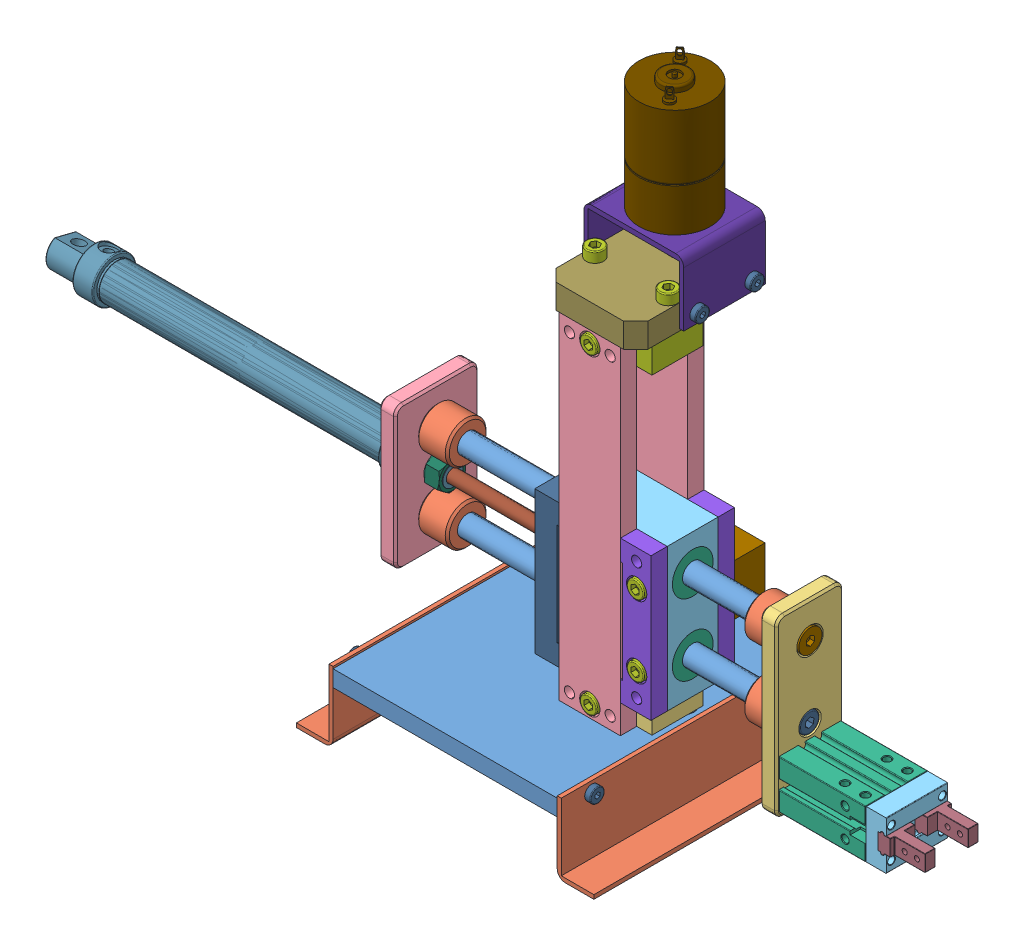
SolidWorks assembly handling, configuration Default. Lengths in mm.
Overall size (436.7 290 125).
70 component instances, 33 part files, 172 mates.
Components (placement in the parent):
- tam de lon-1: tam de lon [Default] at (42.5889 56.6685 101.1963) size (110 8 125)
- khoi do-1: khoi do [Default] at (98.4472 49.4552 163.6963) x (0 0 -1) z (-1 0 0) size (125 35 18)
- khoi do-2: khoi do [Default] at (-13.2695 49.4552 38.6963) x (0 0 1) z (1 0 0) size (125 35 18)
- mieng dem duoi-1: mieng dem duoi [Default] at (71.5889 64.6685 101.1963) size (45 12 25)
- thanh dan huong lon x2-1: thanh dan huong lon x2 [Default] at (71.5889 147.1685 113.6963) x (1 0 0) z (0 -1 0) size (30 8 165)
- thanh dan huong lon x2-2: thanh dan huong lon x2 [Default] at (71.5889 147.1685 88.6963) x (1 0 0) z (0 1 0) size (30 8 165)
- con truot s4 -1: con truot s4  [Default] at (79.0889 78.6685 101.1963) x (-1 0 0) z (0 0 -1) size (45 70 25)
- bac lot-1: bac lot [Default] at (101.5889 96.1685 101.1963) x (0 1 0) z (0 0 1) size (20 12 20)
- bac lot-2: bac lot [Default] at (101.5889 131.1685 101.1963) x (0 1 0) z (0 0 1) size (20 12 20)
- bac lot-3: bac lot [Default] at (56.5889 131.1685 101.1963) x (0 0.381849 -0.924225) z (0 -0.924225 -0.381849) size (20 12 20)
- bac lot-4: bac lot [Default] at (56.5889 96.1685 101.1963) x (0 0.381849 -0.924225) z (0 -0.924225 -0.381849) size (20 12 20)
- mieng dem tren-1: mieng dem tren [Default] at (71.5889 217.6685 101.1963) size (45 12 25)
- thanh dan huong so 2 s4-3: thanh dan huong so 2 s4 [Default] at (94.0889 113.6685 88.6963) x (-1 0 0) z (0 -1 0) size (15 8 70)
- thanh ngang-5: thanh ngang [Default] at (73.0889 110.6685 65.6963) x (-1 0 0) z (0 1 0) size (57 15 25)
- tam dan huong-4: tam dan huong [Default] at (44.5889 113.6685 101.1963) x (0 -1 0) z (0 0 1) size (70 12 41)
- dai oc-1: dai oc [Default] at (71.5889 113.6685 65.6963) x (0 1 0) z (1 0 0) size (16 14 16)
- tam de nho-4: tam de nho [Default] at (71.5889 241.6685 90.6963) x (1 0 0) z (0 0 -1) size (45 12 62)
- dau kep truc vit-2: dau kep truc vit [Default] at (71.5889 256.8685 72.6963) x (-0.681909 0 -0.731437) z (-0.731437 0 0.681909) size (20 25 20)
- vong_dem-2: vong_dem [Default] at (71.5889 229.8685 72.6963) x (0.969315 0 0.245821) z (-0.245821 0 0.969315) size (19.6 2 19.6)
- vit me M8x150mm-2: vit me M8x150mm [Default] at (71.5889 171.8685 72.6963) x (0.994213 0 -0.107422) z (0 1 0) size (10.85 10.06 150.11)
- hex nut gradec_din-2: hex nut gradec_din [Hexagon Nut ISO 4034 - M8 - N] at (71.5889 221.9685 72.6963) x (-0.968146 0 0.250385) z (0 -1 0) size (13 15.01 7.9)
- de dong co-1: de dong co [Default] at (71.6847 246.1685 60.1963) x (1 0 0) z (0 -1 0) size (49 40 31)
- moto-1: moto [Default] at (71.7593 263.8856 80.1944) x (0 -1 0) z (0.022721 0 0.999742) size (78 35 35)
- chot dan huong-1: chot dan huong [Default] at (151.1424 131.1685 101.1963) x (0 0.988897 -0.148604) z (0 0.148604 0.988897) size (10 175 10)
- chot dan huong-2: chot dan huong [Default] at (151.1424 96.1685 101.1963) x (0 0.324021 0.94605) z (0 -0.94605 0.324021) size (10 175 10)
- bac chan-1: bac chan [Default] at (151.1424 131.1685 101.1963) x (0 -0.987145 -0.159829) z (0 0.159829 -0.987145) size (20 15 20)
- bac chan-2: bac chan [Default] at (151.1424 96.1685 101.1963) x (0 1 0) z (0 0 1) size (20 15 20)
- bac chan-3: bac chan [Default] at (-8.8576 131.1685 101.1963) x (0 -0.034971 0.999388) z (0 -0.999388 -0.034971) size (20 15 20)
- bac chan-4: bac chan [Default] at (-8.8576 96.1685 101.1963) x (0 0.99939 -0.03491) z (0 0.03491 0.99939) size (20 15 20)
- ban canh truoc-1: ban canh truoc [Default] at (151.1424 105.6685 101.1963) x (0 0 -1) z (0 -1 0) size (33 8 86)
- ban canh sau-1: ban canh sau [Default] at (-23.8576 113.6685 101.1963) x (0 0 -1) z (0 1 0) size (41 8 70)
- NMHZ2-16D-2: NMHZ2-16D [Default] at (144.1545 75.1106 123.6032) x (0 0 -1) z (1 0 0) size (30.6 23.6 52.5)
  - NMHZ2-16D Slipway-1: NMHZ2-16D Slipway [Default] at (22.4069 2.6078 57.488) size (30.1 23.6 10)
  - NMHZ2-16D cylinder-2: NMHZ2-16D cylinder [Default] at (22.4069 2.6078 14.988) size (30.6 23.6 42.5)
- socket head cap screw_din-2: socket head cap screw_din [DIN 912 M5 x 16 --- 16N] at (94.5889 131.1685 79.8963) x (0 0 1) z (-1 0 0) size (21 8.5 8.5)
- socket head cap screw_din-3: socket head cap screw_din [DIN 912 M5 x 16 --- 16N] at (50.0889 107.1685 66.3963) x (0 0 1) z (-1 0 0) size (21 8.5 8.5)
- socket head cap screw_din-4: socket head cap screw_din [DIN 912 M5 x 16 --- 16N] at (94.5889 120.1685 66.3963) x (0 0 1) z (-1 0 0) size (21 8.5 8.5)
- socket head cap screw_din-5: socket head cap screw_din [DIN 912 M5 x 16 --- 16N] at (94.5889 96.1685 79.8963) x (0 0 1) z (-1 0 0) size (21 8.5 8.5)
- socket head cap screw_din-6: socket head cap screw_din [DIN 912 M5 x 16 --- 16N] at (71.5889 70.6685 79.8963) x (0 0 1) z (-1 0 0) size (21 8.5 8.5)
- socket head cap screw_din-9: socket head cap screw_din [DIN 912 M5 x 8 --- 8N] at (71.5889 70.6685 122.4963) x (0 0 -1) z (1 0 0) size (13 8.5 8.5)
- socket head cap screw_din-10: socket head cap screw_din [DIN 912 M5 x 8 --- 8N] at (45.2889 84.6685 108.6963) size (13 8.5 8.5)
- socket head cap screw_din-11: socket head cap screw_din [DIN 912 M5 x 8 --- 8N] at (45.2889 142.6685 93.6963) size (13 8.5 8.5)
- thanh dan huong s4-1: thanh dan huong s4 [Default] at (94.0889 113.6685 113.6963) x (-1 0 0) z (0 1 0) size (15 8 70)
- socket head cap screw_din-13: socket head cap screw_din [DIN 912 M5 x 12 --- 12N] at (94.5889 96.1685 122.4963) x (0 0 -1) z (1 0 0) size (17 8.5 8.5)
- socket head cap screw_din-14: socket head cap screw_din [DIN 912 M5 x 12 --- 12N] at (94.5889 131.1685 122.4963) x (0 0 -1) z (1 0 0) size (17 8.5 8.5)
- socket head cap screw_din-15: socket head cap screw_din [DIN 912 M5 x 12 --- 12N] at (53.5889 246.6685 101.1963) x (0 -1 0) z (0 0 1) size (17 8.5 8.5)
- socket head cap screw_din-16: socket head cap screw_din [DIN 912 M5 x 12 --- 12N] at (89.5889 246.6685 101.1963) x (0 -1 0) z (0 0 1) size (17 8.5 8.5)
- socket head cap screw_din-17: socket head cap screw_din [DIN 912 M5 x 12 --- 12N] at (71.5889 223.6685 79.8963) x (0 0 1) z (-1 0 0) size (17 8.5 8.5)
- socket head cap screw_din-18: socket head cap screw_din [DIN 912 M5 x 12 --- 12N] at (71.5889 223.6685 122.4963) x (0 0 -1) z (1 0 0) size (17 8.5 8.5)
- socket csink head cap screw 10642_din-2: socket csink head cap screw 10642_din [EN ISO 10642 - M6 x 8 - 8N] at (-32.0776 131.1685 101.1963) x (1 0 0) z (0 0.02259 0.999745) size (8 11.34 11.34)
- socket csink head cap screw 10642_din-3: socket csink head cap screw 10642_din [EN ISO 10642 - M6 x 8 - 8N] at (159.3624 131.1685 101.1963) x (-1 0 0) z (0 -0.022602 -0.999745) size (8 11.34 11.34)
- socket head thin cap screw_din-2: socket head thin cap screw_din [DIN 7984 - M6 x 10 --- 7N] at (158.9424 96.1685 101.1963) x (-1 0 0) z (0 0.924225 0.381849) size (14 10 10)
- socket head thin cap screw_din-4: socket head thin cap screw_din [DIN 7984 - M6 x 10 --- 7N] at (-31.6576 96.1685 101.1963) size (14 10 10)
- socket head thin cap screw_din-5: socket head thin cap screw_din [DIN 7984 - M4 x 6 --- 3.9N] at (-17.2111 60.6685 53.6963) size (8.8 7 7)
- socket head thin cap screw_din-6: socket head thin cap screw_din [DIN 7984 - M4 x 6 --- 3.9N] at (-17.2111 60.6685 148.6963) size (8.8 7 7)
- socket head thin cap screw_din-7: socket head thin cap screw_din [DIN 7984 - M4 x 6 --- 3.9N] at (102.3889 60.6685 53.6963) x (-1 0 0) z (0 0.924225 0.381849) size (8.8 7 7)
- socket head thin cap screw_din-8: socket head thin cap screw_din [DIN 7984 - M4 x 6 --- 3.9N] at (102.3889 60.6685 148.6963) x (-1 0 0) z (0 0.924225 0.381849) size (8.8 7 7)
- socket head thin cap screw_din-10: socket head thin cap screw_din [DIN 7984 - M4 x 12 --- 9.9N] at (152.7424 70.3685 112.1963) size (14.8 7 7)
- socket head thin cap screw_din-11: socket head thin cap screw_din [DIN 7984 - M4 x 12 --- 9.9N] at (152.7424 85.3685 90.1963) size (14.8 7 7)
- socket head thin cap screw_din-13: socket head thin cap screw_din [DIN 7984 - M4 x 6 --- 3.9N] at (98.9847 235.6685 66.6963) x (-1 0 0) z (0 0.924225 0.381849) size (8.8 7 7)
- socket head thin cap screw_din-14: socket head thin cap screw_din [DIN 7984 - M4 x 6 --- 3.9N] at (98.9847 235.6685 93.6963) x (-1 0 0) z (0 0.924225 0.381849) size (8.8 7 7)
- socket head thin cap screw_din-15: socket head thin cap screw_din [DIN 7984 - M4 x 6 --- 3.9N] at (44.3847 235.6685 66.6963) size (8.8 7 7)
- socket head thin cap screw_din-16: socket head thin cap screw_din [DIN 7984 - M4 x 6 --- 3.9N] at (44.3847 235.6685 93.6963) size (8.8 7 7)
- socket head thin cap screw_din-18: socket head thin cap screw_din [DIN 7984 - M3 x 5 --- 3.5N] at (67.1565 252.8685 67.942) x (0.681909 0 0.731437) z (0.731403 -0.009583 -0.681878) size (7 5.5 5.5)
- Rod-1: Rod [Default] at (-92.4392 113.6685 101.1963) x (0 0.994852 -0.101337) z (0 -0.101337 -0.994852) size (6.2 165 6.2)
- Nut 5-1: Nut 5 [Default] at (55.0889 113.6685 101.1963) x (0 -0.278581 0.960413) z (0 0.960413 0.278581) size (11.32 3 9.8)
- NMHZ2-16D air claw-1: NMHZ2-16D air claw [Default] at (209.6424 77.7185 98.1463) x (0 0 -1) z (1 0 0) size (12 10 21)
- NMHZ2-16D air claw-2: NMHZ2-16D air claw [Default] at (209.6424 77.7185 104.2463) x (0 0 1) z (1 0 0) size (12 10 21)
- 16 X 100 Cylinder bore-3: 16 X 100 Cylinder bore [Default] at (-112.0576 113.6685 101.1963) x (0 0.970405 -0.241483) z (-1 0 0) size (21.5 21.5 192)
- hex nut style 2 fine gradeab_din-4: hex nut style 2 fine gradeab_din [Hexagon Nut ISO 8674 - M8 x 1 - W - N] at (-16.3576 113.6685 101.1963) x (0 0.810685 -0.585482) z (1 0 0) size (13 15.01 7.5)
Mates (geometry in assembly coordinates):
- Parallel1: parallel anti-aligned: plane of tam de lon-1 through (42.5889 64.6685 101.1963) normal (0 1 0); plane of khoi do-1 through (97.5889 30.6685 38.6963) normal (0 -1 0)
- Parallel2: parallel anti-aligned: plane of tam de lon-1 through (97.5889 64.6685 38.6963) normal (1 0 0); plane of khoi do-1 through (97.5889 30.6685 38.6963) normal (-1 0 0)
- Concentric1: concentric aligned: cylinder of tam de lon-1 through (82.5889 60.6685 53.6963) axis (1 0 0) radius 2.5; cylinder of khoi do-1 through (-25.4111 60.6685 53.6963) axis (1 0 0) radius 2.5
- Coincident1: coincident anti-aligned: plane of tam de lon-1 through (97.5889 64.6685 38.6963) normal (1 0 0); plane of khoi do-1 through (97.5889 30.6685 38.6963) normal (-1 0 0)
- Parallel3: parallel anti-aligned: plane of tam de lon-1 through (42.5889 64.6685 101.1963) normal (0 1 0); plane of khoi do-2 through (-12.4111 30.6685 163.6963) normal (0 -1 0)
- Parallel4: parallel anti-aligned: plane of tam de lon-1 through (-12.4111 64.6685 38.6963) normal (-1 0 0); plane of khoi do-2 through (-12.4111 30.6685 163.6963) normal (1 0 0)
- Concentric2: concentric aligned: cylinder of tam de lon-1 through (2.5889 60.6685 148.6963) axis (-1 0 0) radius 2.5; cylinder of khoi do-2 through (110.5889 60.6685 148.6963) axis (-1 0 0) radius 2.5
- Coincident2: coincident anti-aligned: plane of tam de lon-1 through (-12.4111 64.6685 38.6963) normal (-1 0 0); plane of khoi do-2 through (-12.4111 30.6685 163.6963) normal (1 0 0)
- Concentric3: concentric aligned: cylinder of tam de lon-1 through (89.5889 56.6685 93.6963) axis (0 1 0) radius 2.75; cylinder of mieng dem duoi-1 through (89.5889 64.6685 93.6963) axis (0 1 0) radius 2.5
- Concentric4: concentric aligned: cylinder of tam de lon-1 through (53.5889 56.6685 108.6963) axis (0 1 0) radius 2.75; cylinder of mieng dem duoi-1 through (53.5889 64.6685 108.6963) axis (0 1 0) radius 2.5
- Coincident3: coincident anti-aligned: plane of tam de lon-1 through (42.5889 64.6685 101.1963) normal (0 1 0); plane of mieng dem duoi-1 through (71.5889 64.6685 101.1963) normal (0 -1 0)
- Parallel6: parallel anti-aligned: plane of mieng dem duoi-1 through (71.5889 76.6685 101.1963) normal (0 1 0); plane of thanh dan huong lon x2-1 through (56.5889 64.6685 121.6963) normal (0 -1 0)
- Parallel7: parallel anti-aligned: plane of mieng dem duoi-1 through (49.0889 76.6685 113.6963) normal (0 0 1); plane of thanh dan huong lon x2-1 through (71.5889 147.1685 113.6963) normal (0 0 -1)
- Concentric5: concentric anti-aligned: cylinder of mieng dem duoi-1 through (81.5889 70.6685 160.6963) axis (0 0 -1) radius 2.5; cylinder of thanh dan huong lon x2-1 through (81.5889 70.6685 80.4963) axis (0 0 1) radius 2.5
- Coincident4: coincident anti-aligned: plane of mieng dem duoi-1 through (49.0889 76.6685 113.6963) normal (0 0 1); plane of thanh dan huong lon x2-1 through (71.5889 147.1685 113.6963) normal (0 0 -1)
- Parallel8: parallel anti-aligned: plane of mieng dem duoi-1 through (71.5889 76.6685 101.1963) normal (0 1 0); plane of thanh dan huong lon x2-2 through (56.5889 64.6685 80.6963) normal (0 -1 0)
- Parallel9: parallel anti-aligned: plane of mieng dem duoi-1 through (49.0889 76.6685 88.6963) normal (0 0 -1); plane of thanh dan huong lon x2-2 through (71.5889 147.1685 88.6963) normal (0 0 1)
- Concentric6: concentric aligned: cylinder of mieng dem duoi-1 through (81.5889 70.6685 160.6963) axis (0 0 -1) radius 2.5; cylinder of thanh dan huong lon x2-2 through (81.5889 70.6685 121.8963) axis (0 0 -1) radius 2.5
- Coincident5: coincident anti-aligned: plane of mieng dem duoi-1 through (49.0889 76.6685 88.6963) normal (0 0 -1); plane of thanh dan huong lon x2-2 through (71.5889 147.1685 88.6963) normal (0 0 1)
- Parallel10: parallel anti-aligned: plane of mieng dem duoi-1 through (94.0889 76.6685 88.6963) normal (1 0 0); plane of con truot s4 -1 through (56.5889 148.6685 113.6963) normal (-1 0 0)
- Parallel11: parallel aligned: plane of mieng dem duoi-1 through (71.5889 76.6685 101.1963) normal (0 1 0); plane of con truot s4 -1 through (79.0889 148.6685 101.1963) normal (0 1 0)
- Coincident6: coincident anti-aligned: plane of thanh dan huong lon x2-2 through (71.5889 147.1685 88.6963) normal (0 0 1); plane of con truot s4 -1 through (101.5889 148.6685 88.6963) normal (0 0 -1)
- Concentric7: concentric anti-aligned: cylinder of con truot s4 -1 through (126.5889 96.1685 101.1963) axis (-1 0 0) radius 6; cylinder of bac lot-1 through (89.5889 96.1685 101.1963) axis (1 0 0) radius 6
- Coincident14: coincident anti-aligned: plane of con truot s4 -1 through (99.5889 96.1685 101.1963) normal (1 0 0); plane of bac lot-1 through (99.5889 96.1685 101.1963) normal (-1 0 0)
- Concentric8: concentric anti-aligned: cylinder of con truot s4 -1 through (126.5889 131.1685 101.1963) axis (-1 0 0) radius 6; cylinder of bac lot-2 through (89.5889 131.1685 101.1963) axis (1 0 0) radius 6
- Coincident15: coincident anti-aligned: plane of con truot s4 -1 through (99.5889 131.1685 101.1963) normal (1 0 0); plane of bac lot-2 through (99.5889 131.1685 101.1963) normal (-1 0 0)
- Concentric9: concentric aligned: cylinder of con truot s4 -1 through (126.5889 131.1685 101.1963) axis (-1 0 0) radius 6; cylinder of bac lot-3 through (68.5889 131.1685 101.1963) axis (-1 0 0) radius 6
- Coincident16: coincident anti-aligned: plane of con truot s4 -1 through (58.5889 131.1685 101.1963) normal (-1 0 0); plane of bac lot-3 through (58.5889 131.1685 101.1963) normal (1 0 0)
- Concentric10: concentric aligned: cylinder of con truot s4 -1 through (126.5889 96.1685 101.1963) axis (-1 0 0) radius 6; cylinder of bac lot-4 through (68.5889 96.1685 101.1963) axis (-1 0 0) radius 6
- Coincident18: coincident anti-aligned: plane of con truot s4 -1 through (58.5889 96.1685 101.1963) normal (-1 0 0); plane of bac lot-4 through (58.5889 96.1685 101.1963) normal (1 0 0)
- Parallel23: parallel aligned: plane of thanh dan huong lon x2-2 through (56.5889 229.6685 80.6963) normal (0 1 0); plane of mieng dem tren-1 through (71.5889 229.6685 101.1963) normal (0 1 0)
- Concentric12: concentric aligned: cylinder of thanh dan huong lon x2-2 through (61.5889 223.6685 121.8963) axis (0 0 -1) radius 2.5; cylinder of mieng dem tren-1 through (61.5889 223.6685 160.6963) axis (0 0 -1) radius 2.5
- Coincident21: coincident anti-aligned: plane of thanh dan huong lon x2-2 through (71.5889 147.1685 88.6963) normal (0 0 1); plane of mieng dem tren-1 through (49.0889 229.6685 88.6963) normal (0 0 -1)
- Parallel38: parallel aligned: plane of con truot s4 -1 through (79.0889 148.6685 101.1963) normal (0 1 0); plane of thanh dan huong so 2 s4-3 through (101.5889 148.6685 80.6963) normal (0 1 0)
- Parallel39: parallel anti-aligned: plane of con truot s4 -1 through (101.5889 148.6685 88.6963) normal (0 0 -1); plane of thanh dan huong so 2 s4-3 through (94.0889 113.6685 88.6963) normal (0 0 1)
- Coincident32: coincident aligned: plane of con truot s4 -1 through (79.0889 148.6685 101.1963) normal (0 1 0); plane of thanh dan huong so 2 s4-3 through (101.5889 148.6685 80.6963) normal (0 1 0)
- Coincident33: coincident aligned: plane of con truot s4 -1 through (101.5889 148.6685 113.6963) normal (1 0 0); plane of thanh dan huong so 2 s4-3 through (101.5889 148.6685 80.6963) normal (1 0 0)
- Coincident34: coincident anti-aligned: plane of con truot s4 -1 through (101.5889 148.6685 88.6963) normal (0 0 -1); plane of thanh dan huong so 2 s4-3 through (94.0889 113.6685 88.6963) normal (0 0 1)
- Coincident36: coincident anti-aligned: plane of thanh dan huong lon x2-2 through (86.5889 64.6685 80.6963) normal (1 0 0); plane of thanh dan huong so 2 s4-3 through (86.5889 148.6685 80.6963) normal (-1 0 0)
- Parallel42: parallel anti-aligned: plane of thanh dan huong so 2 s4-3 through (101.5889 148.6685 80.6963) normal (0 1 0); plane of thanh ngang-5 through (101.5889 101.1685 80.6963) normal (0 -1 0)
- Concentric26: concentric aligned: cylinder of thanh dan huong so 2 s4-3 through (94.5889 120.1685 152.8963) axis (0 0 -1) radius 2.5; cylinder of thanh ngang-5 through (94.5889 120.1685 124.3963) axis (0 0 -1) radius 2.75
- Parallel46: parallel aligned: plane of con truot s4 -1 through (79.0889 148.6685 101.1963) normal (0 1 0); plane of tam dan huong-4 through (56.5889 148.6685 80.6963) normal (0 1 0)
- Parallel47: parallel anti-aligned: plane of con truot s4 -1 through (56.5889 148.6685 113.6963) normal (-1 0 0); plane of tam dan huong-4 through (55.5889 138.6685 33.6963) normal (1 0 0)
- Coincident40: coincident anti-aligned: plane of con truot s4 -1 through (56.5889 148.6685 113.6963) normal (-1 0 0); plane of tam dan huong-4 through (56.5889 113.6685 101.1963) normal (1 0 0)
- Concentric29: concentric aligned: cylinder of con truot s4 -1 through (71.5889 142.6685 93.6963) axis (-1 0 0) radius 2.5; cylinder of tam dan huong-4 through (132.5889 142.6685 93.6963) axis (-1 0 0) radius 2.75
- Coincident41: coincident anti-aligned: plane of thanh dan huong so 2 s4-3 through (94.0889 113.6685 80.6963) normal (0 0 -1); plane of thanh ngang-5 through (73.0889 110.6685 80.6963) normal (0 0 1)
- Parallel48: parallel anti-aligned: plane of thanh ngang-5 through (73.0889 110.6685 65.6963) normal (0 0 -1); plane of dai oc-1 through (80.1238 134.6685 79.6963) normal (0 0 1)
- Concentric30: concentric anti-aligned: cylinder of thanh ngang-5 through (71.5889 -44.8315 72.6963) axis (0 1 0) radius 5; cylinder of dai oc-1 through (71.5889 134.6685 72.6963) axis (0 -1 0) radius 4
- Concentric31: concentric aligned: cylinder of thanh ngang-5 through (71.5889 113.6685 236.6963) axis (0 0 -1) radius 8; cylinder of dai oc-1 through (71.5889 113.6685 79.6963) axis (0 0 -1) radius 8
- Parallel53: parallel anti-aligned: plane of mieng dem tren-1 through (71.5889 229.6685 101.1963) normal (0 1 0); plane of tam de nho-4 through (71.5889 229.6685 90.6963) normal (0 -1 0)
- Parallel54: parallel anti-aligned: plane of mieng dem tren-1 through (94.0889 229.6685 88.6963) normal (1 0 0); plane of tam de nho-4 through (49.0889 229.6685 121.6963) normal (-1 0 0)
- Concentric32: concentric anti-aligned: cylinder of mieng dem tren-1 through (53.5889 157.6685 101.1963) axis (0 1 0) radius 2.5; cylinder of tam de nho-4 through (53.5889 241.6685 101.1963) axis (0 -1 0) radius 2.75
- Coincident45: coincident anti-aligned: plane of mieng dem tren-1 through (71.5889 229.6685 101.1963) normal (0 1 0); plane of tam de nho-4 through (71.5889 229.6685 90.6963) normal (0 -1 0)
- Parallel55: parallel anti-aligned: plane of tam de nho-4 through (71.5889 241.6685 90.6963) normal (0 1 0); plane of dau kep truc vit-2 through (71.5889 231.8685 72.6963) normal (0 -1 0)
- Concentric33: concentric aligned: cylinder of tam de nho-4 through (71.5889 241.6685 72.6963) axis (0 -1 0) radius 7; cylinder of dau kep truc vit-2 through (71.5889 241.6685 72.6963) axis (0 -1 0) radius 7
- Coincident46: coincident anti-aligned: plane of tam de nho-4 through (71.5889 241.6685 90.6963) normal (0 1 0); plane of dau kep truc vit-2 through (71.5889 241.6685 72.6963) normal (0 -1 0)
- Concentric34: concentric aligned: cylinder of dau kep truc vit-2 through (71.5889 246.8685 72.6963) axis (0 -1 0) radius 4; cylinder of vong_dem-2 through (71.5889 231.8685 72.6963) axis (0 -1 0) radius 4.25
- Coincident47: coincident anti-aligned: plane of dau kep truc vit-2 through (71.5889 231.8685 72.6963) normal (0 -1 0); plane of vong_dem-2 through (71.5889 231.8685 72.6963) normal (0 1 0)
- Concentric35: concentric anti-aligned: cylinder of dau kep truc vit-2 through (71.5889 246.8685 72.6963) axis (0 -1 0) radius 4; cylinder of vit me M8x150mm-2 through (71.5889 171.8685 72.6963) axis (0 1 0) radius 3.933
- Coincident48: coincident anti-aligned: plane of dau kep truc vit-2 through (71.5889 246.8685 72.6963) normal (0 -1 0); plane of vit me M8x150mm-2 through (71.5889 246.8685 72.6963) normal (0 1 0)
- Concentric37: concentric anti-aligned: cylinder of vit me M8x150mm-2 through (71.5889 171.8685 72.6963) axis (0 1 0) radius 3.933; cylinder of hex nut gradec_din-2 through (71.5889 229.8685 72.6963) axis (0 -1 0) radius 3.4
- Coincident49: coincident anti-aligned: plane of vong_dem-2 through (71.5889 229.8685 72.6963) normal (0 -1 0); plane of hex nut gradec_din-2 through (69.7096 229.8685 65.4298) normal (0 1 0)
- Lock1: lock: unknown of vit me M8x150mm-2; unknown of hex nut gradec_din-2
- Lock2: lock: unknown of dau kep truc vit-2; unknown of hex nut gradec_din-2
- Concentric38: concentric anti-aligned: cylinder of tam de nho-4 through (78.0889 235.6685 66.6963) axis (1 0 0) radius 2; cylinder of de dong co-1 through (123.1847 235.6685 66.6963) axis (-1 0 0) radius 2.25
- Concentric39: concentric anti-aligned: cylinder of tam de nho-4 through (78.0889 235.6685 93.6963) axis (1 0 0) radius 2; cylinder of de dong co-1 through (123.1847 235.6685 93.6963) axis (-1 0 0) radius 2.25
- Coincident50: coincident anti-aligned: plane of tam de nho-4 through (94.0889 229.6685 121.6963) normal (1 0 0); plane of de dong co-1 through (94.0889 259.3217 523.1963) normal (-1 0 0)
- Parallel56: parallel anti-aligned: plane of de dong co-1 through (47.1847 261.6685 100.1963) normal (0 1 0); plane of moto-1 through (71.7593 261.6685 80.1944) normal (0 -1 0)
- Concentric40: concentric aligned: cylinder of dau kep truc vit-2 through (71.5889 245.8685 72.6963) axis (0 1 0) radius 2.75; cylinder of moto-1 through (71.5889 242.6685 72.6963) axis (0 1 0) radius 2.75
- Coincident52: coincident anti-aligned: plane of de dong co-1 through (47.1847 261.6685 100.1963) normal (0 1 0); plane of moto-1 through (71.7593 261.6685 80.1944) normal (0 -1 0)
- Lock3: lock: unknown of de dong co-1; unknown of moto-1
- Concentric41: concentric anti-aligned: cylinder of bac lot-2 through (116.5889 131.1685 101.1963) axis (-1 0 0) radius 5; cylinder of chot dan huong-1 through (-121.8576 131.1685 101.1963) axis (1 0 0) radius 5
- Concentric42: concentric anti-aligned: cylinder of bac lot-1 through (116.5889 96.1685 101.1963) axis (-1 0 0) radius 5; cylinder of chot dan huong-2 through (-121.8576 96.1685 101.1963) axis (1 0 0) radius 5
- Concentric43: concentric anti-aligned: cylinder of chot dan huong-1 through (-121.8576 131.1685 101.1963) axis (1 0 0) radius 5; cylinder of bac chan-1 through (151.1424 131.1685 101.1963) axis (-1 0 0) radius 5
- Coincident53: coincident aligned: plane of chot dan huong-1 through (151.1424 131.1685 101.1963) normal (1 0 0); plane of bac chan-1 through (151.1424 131.1685 101.1963) normal (1 0 0)
- Concentric44: concentric anti-aligned: cylinder of chot dan huong-2 through (-121.8576 96.1685 101.1963) axis (1 0 0) radius 5; cylinder of bac chan-2 through (151.1424 96.1685 101.1963) axis (-1 0 0) radius 5
- Coincident54: coincident aligned: plane of chot dan huong-2 through (151.1424 96.1685 101.1963) normal (1 0 0); plane of bac chan-2 through (151.1424 96.1685 101.1963) normal (1 0 0)
- Concentric45: concentric anti-aligned: cylinder of chot dan huong-1 through (-121.8576 131.1685 101.1963) axis (1 0 0) radius 5; cylinder of bac chan-3 through (-8.8576 131.1685 101.1963) axis (-1 0 0) radius 5
- Coincident55: coincident aligned: plane of chot dan huong-1 through (-23.8576 131.1685 101.1963) normal (-1 0 0); plane of bac chan-3 through (-23.8576 131.1685 101.1963) normal (-1 0 0)
- Coincident57: coincident aligned: plane of chot dan huong-2 through (-23.8576 96.1685 101.1963) normal (-1 0 0); plane of bac chan-4 through (-23.8576 96.1685 101.1963) normal (-1 0 0)
- Concentric47: concentric aligned: cylinder of chot dan huong-1 through (131.1424 131.1685 101.1963) axis (1 0 0) radius 3; cylinder of ban canh truoc-1 through (151.1424 131.1685 101.1963) axis (1 0 0) radius 3.3
- Concentric48: concentric aligned: cylinder of chot dan huong-2 through (131.1424 96.1685 101.1963) axis (1 0 0) radius 3; cylinder of ban canh truoc-1 through (151.1424 96.1685 101.1963) axis (1 0 0) radius 3.3
- Coincident58: coincident anti-aligned: plane of chot dan huong-1 through (151.1424 131.1685 101.1963) normal (1 0 0); plane of ban canh truoc-1 through (151.1424 105.6685 101.1963) normal (-1 0 0)
- Coincident59: coincident anti-aligned: plane of chot dan huong-2 through (151.1424 96.1685 101.1963) normal (1 0 0); plane of ban canh truoc-1 through (151.1424 105.6685 101.1963) normal (-1 0 0)
- Concentric49: concentric aligned: cylinder of chot dan huong-1 through (-3.8576 131.1685 101.1963) axis (-1 0 0) radius 3; cylinder of ban canh sau-1 through (-23.8576 131.1685 101.1963) axis (-1 0 0) radius 3.3
- Concentric50: concentric aligned: cylinder of chot dan huong-2 through (-3.8576 96.1685 101.1963) axis (-1 0 0) radius 3; cylinder of ban canh sau-1 through (-23.8576 96.1685 101.1963) axis (-1 0 0) radius 3.3
- Coincident60: coincident anti-aligned: plane of chot dan huong-1 through (-23.8576 131.1685 101.1963) normal (-1 0 0); plane of ban canh sau-1 through (-23.8576 113.6685 101.1963) normal (1 0 0)
- Coincident61: coincident anti-aligned: plane of chot dan huong-2 through (-23.8576 96.1685 101.1963) normal (-1 0 0); plane of ban canh sau-1 through (-23.8576 113.6685 101.1963) normal (1 0 0)
- Concentric55: concentric anti-aligned: cylinder of ban canh truoc-1 through (151.1424 70.3685 112.1963) axis (1 0 0) radius 2.25; cylinder of NMHZ2-16D-2/NMHZ2-16D cylinder-2 through (174.1424 70.3685 112.1963) axis (-1 0 0) radius 2
- Concentric56: concentric anti-aligned: cylinder of ban canh truoc-1 through (151.1424 85.3685 90.1963) axis (1 0 0) radius 2.25; cylinder of NMHZ2-16D-2/NMHZ2-16D cylinder-2 through (174.1424 85.3685 90.1963) axis (-1 0 0) radius 2
- Coincident62: coincident anti-aligned: plane of ban canh truoc-1 through (159.1424 105.6685 101.1963) normal (1 0 0); plane of NMHZ2-16D-2/NMHZ2-16D cylinder-2 through (159.1424 77.7185 101.1963) normal (-1 0 0)
- Concentric57: concentric anti-aligned: cylinder of chot dan huong-2 through (-121.8576 96.1685 101.1963) axis (1 0 0) radius 5; cylinder of bac chan-4 through (-8.8576 96.1685 101.1963) axis (-1 0 0) radius 5
- Concentric61: concentric aligned: cylinder of thanh dan huong so 2 s4-3 through (94.5889 131.1685 88.6963) axis (0 0 -1) radius 2.75; cylinder of socket head cap screw_din-2 through (94.5889 131.1685 48.1463) axis (0 0 -1) radius 4.25
- Coincident66: coincident anti-aligned: plane of thanh dan huong so 2 s4-3 through (94.5889 131.1685 84.8963) normal (0 0 -1); plane of socket head cap screw_din-2 through (94.5889 135.4185 84.8963) normal (0 0 1)
- Concentric62: concentric aligned: cylinder of thanh ngang-5 through (50.0889 107.1685 71.3963) axis (0 0 -1) radius 5; cylinder of socket head cap screw_din-3 through (50.0889 107.1685 34.6463) axis (0 0 -1) radius 4.25
- Coincident67: coincident anti-aligned: plane of thanh ngang-5 through (50.0889 107.1685 71.3963) normal (0 0 -1); plane of socket head cap screw_din-3 through (50.0889 111.4185 71.3963) normal (0 0 1)
- Concentric63: concentric aligned: cylinder of thanh ngang-5 through (94.5889 120.1685 124.3963) axis (0 0 -1) radius 2.75; cylinder of socket head cap screw_din-4 through (94.5889 120.1685 34.6463) axis (0 0 -1) radius 4.25
- Coincident68: coincident anti-aligned: plane of thanh ngang-5 through (94.5889 120.1685 71.3963) normal (0 0 -1); plane of socket head cap screw_din-4 through (94.5889 124.4185 71.3963) normal (0 0 1)
- Concentric64: concentric aligned: cylinder of thanh dan huong so 2 s4-3 through (94.5889 96.1685 88.6963) axis (0 0 -1) radius 2.75; cylinder of socket head cap screw_din-5 through (94.5889 96.1685 48.1463) axis (0 0 -1) radius 4.25
- Coincident69: coincident anti-aligned: plane of thanh dan huong so 2 s4-3 through (94.5889 96.1685 84.8963) normal (0 0 -1); plane of socket head cap screw_din-5 through (94.5889 100.4185 84.8963) normal (0 0 1)
- Concentric651: concentric aligned: cylinder of thanh dan huong lon x2-2 through (71.5889 70.6685 88.6963) axis (0 0 -1) radius 2.75; cylinder of socket head cap screw_din-6 through (71.5889 70.6685 48.1463) axis (0 0 -1) radius 4.25
- Coincident701: coincident anti-aligned: plane of thanh dan huong lon x2-2 through (71.5889 70.6685 84.8963) normal (0 0 -1); plane of socket head cap screw_din-6 through (71.5889 74.9185 84.8963) normal (0 0 1)
- Concentric66: concentric aligned: cylinder of thanh dan huong lon x2-1 through (71.5889 70.6685 113.6963) axis (0 0 1) radius 2.75; cylinder of socket head cap screw_din-9 through (71.5889 70.6685 154.2463) axis (0 0 1) radius 4.25
- Coincident71: coincident anti-aligned: plane of thanh dan huong lon x2-1 through (71.5889 70.6685 117.4963) normal (0 0 1); plane of socket head cap screw_din-9 through (71.5889 74.9185 117.4963) normal (0 0 -1)
- Concentric67: concentric aligned: cylinder of tam dan huong-4 through (132.5889 84.6685 108.6963) axis (-1 0 0) radius 2.75; cylinder of socket head cap screw_din-10 through (13.5389 84.6685 108.6963) axis (-1 0 0) radius 4.25
- Coincident72: coincident anti-aligned: plane of tam dan huong-4 through (50.2889 84.6685 108.6963) normal (-1 0 0); plane of socket head cap screw_din-10 through (50.2889 88.9185 108.6963) normal (1 0 0)
- Concentric68: concentric aligned: cylinder of tam dan huong-4 through (132.5889 142.6685 93.6963) axis (-1 0 0) radius 2.75; cylinder of socket head cap screw_din-11 through (13.5389 142.6685 93.6963) axis (-1 0 0) radius 4.25
- Coincident73: coincident anti-aligned: plane of tam dan huong-4 through (50.2889 142.6685 93.6963) normal (-1 0 0); plane of socket head cap screw_din-11 through (50.2889 146.9185 93.6963) normal (1 0 0)
- Parallel62: parallel aligned: plane of con truot s4 -1 through (101.5889 148.6685 113.6963) normal (0 0 1); plane of thanh dan huong s4-1 through (94.0889 113.6685 121.6963) normal (0 0 1)
- Parallel63: parallel aligned: plane of con truot s4 -1 through (101.5889 148.6685 113.6963) normal (1 0 0); plane of thanh dan huong s4-1 through (101.5889 78.6685 121.6963) normal (1 0 0)
- Concentric71: concentric anti-aligned: cylinder of con truot s4 -1 through (94.5889 96.1685 124.6963) axis (0 0 -1) radius 2.5; cylinder of thanh dan huong s4-1 through (94.5889 96.1685 113.6963) axis (0 0 1) radius 2.75
- Coincident76: coincident anti-aligned: plane of con truot s4 -1 through (101.5889 148.6685 113.6963) normal (0 0 1); plane of thanh dan huong s4-1 through (94.0889 113.6685 113.6963) normal (0 0 -1)
- Concentric72: concentric aligned: cylinder of thanh dan huong s4-1 through (94.5889 96.1685 113.6963) axis (0 0 1) radius 2.75; cylinder of socket head cap screw_din-13 through (94.5889 96.1685 154.2463) axis (0 0 1) radius 4.25
- Coincident77: coincident anti-aligned: plane of thanh dan huong s4-1 through (94.5889 96.1685 117.4963) normal (0 0 1); plane of socket head cap screw_din-13 through (94.5889 100.4185 117.4963) normal (0 0 -1)
- Concentric73: concentric aligned: cylinder of thanh dan huong s4-1 through (94.5889 131.1685 113.6963) axis (0 0 1) radius 2.75; cylinder of socket head cap screw_din-14 through (94.5889 131.1685 154.2463) axis (0 0 1) radius 4.25
- Coincident78: coincident anti-aligned: plane of thanh dan huong s4-1 through (94.5889 131.1685 117.4963) normal (0 0 1); plane of socket head cap screw_din-14 through (94.5889 135.4185 117.4963) normal (0 0 -1)
- Concentric74: concentric anti-aligned: cylinder of tam de nho-4 through (53.5889 241.6685 101.1963) axis (0 -1 0) radius 2.75; cylinder of socket head cap screw_din-15 through (53.5889 278.4185 101.1963) axis (0 1 0) radius 4.25
- Coincident79: coincident anti-aligned: plane of tam de nho-4 through (71.5889 241.6685 90.6963) normal (0 1 0); plane of socket head cap screw_din-15 through (57.8389 241.6685 101.1963) normal (0 -1 0)
- Concentric75: concentric anti-aligned: cylinder of tam de nho-4 through (89.5889 241.6685 101.1963) axis (0 -1 0) radius 2.75; cylinder of socket head cap screw_din-16 through (89.5889 278.4185 101.1963) axis (0 1 0) radius 4.25
- Coincident80: coincident anti-aligned: plane of tam de nho-4 through (71.5889 241.6685 90.6963) normal (0 1 0); plane of socket head cap screw_din-16 through (93.8389 241.6685 101.1963) normal (0 -1 0)
- Concentric76: concentric aligned: cylinder of thanh dan huong lon x2-2 through (71.5889 223.6685 84.8963) axis (0 0 -1) radius 5; cylinder of socket head cap screw_din-17 through (71.5889 223.6685 48.1463) axis (0 0 -1) radius 4.25
- Coincident81: coincident anti-aligned: plane of thanh dan huong lon x2-2 through (71.5889 223.6685 84.8963) normal (0 0 -1); plane of socket head cap screw_din-17 through (71.5889 227.9185 84.8963) normal (0 0 1)
- Concentric77: concentric aligned: cylinder of thanh dan huong lon x2-1 through (71.5889 223.6685 113.6963) axis (0 0 1) radius 2.75; cylinder of socket head cap screw_din-18 through (71.5889 223.6685 154.2463) axis (0 0 1) radius 4.25
- Coincident82: coincident anti-aligned: plane of thanh dan huong lon x2-1 through (71.5889 223.6685 117.4963) normal (0 0 1); plane of socket head cap screw_din-18 through (71.5889 227.9185 117.4963) normal (0 0 -1)
- Coincident83: coincident aligned: cone of ban canh sau-1 through (-28.6576 131.1685 101.1963) axis (1 0 0); cone of socket csink head cap screw 10642_din-2 through (-31.0276 131.1685 101.1963) axis (1 0 0)
- Coincident84: coincident aligned: cone of ban canh truoc-1 through (155.9424 131.1685 101.1963) axis (-1 0 0); cone of socket csink head cap screw 10642_din-3 through (158.3124 131.1685 101.1963) axis (-1 0 0)
- Concentric78: concentric aligned: cylinder of ban canh truoc-1 through (151.1424 96.1685 101.1963) axis (1 0 0) radius 3.3; cylinder of socket head thin cap screw_din-2 through (190.6924 96.1685 101.1963) axis (1 0 0) radius 5
- Coincident85: coincident anti-aligned: plane of ban canh truoc-1 through (154.9424 96.1685 101.1963) normal (1 0 0); plane of socket head thin cap screw_din-2 through (154.9424 94.2592 105.8174) normal (-1 0 0)
- Concentric79: concentric aligned: cylinder of ban canh sau-1 through (-23.8576 96.1685 101.1963) axis (-1 0 0) radius 3.3; cylinder of socket head thin cap screw_din-4 through (-63.4076 96.1685 101.1963) axis (-1 0 0) radius 5
- Coincident86: coincident anti-aligned: plane of ban canh sau-1 through (-27.6576 96.1685 101.1963) normal (-1 0 0); plane of socket head thin cap screw_din-4 through (-27.6576 101.1685 101.1963) normal (1 0 0)
- Concentric80: concentric aligned: cylinder of khoi do-2 through (110.5889 60.6685 53.6963) axis (-1 0 0) radius 2.5; cylinder of socket head thin cap screw_din-5 through (-48.9611 60.6685 53.6963) axis (-1 0 0) radius 3.5
- Coincident87: coincident anti-aligned: plane of khoi do-2 through (-14.4111 32.6685 163.6963) normal (-1 0 0); plane of socket head thin cap screw_din-5 through (-14.4111 64.1685 53.6963) normal (1 0 0)
- Concentric81: concentric aligned: cylinder of khoi do-2 through (110.5889 60.6685 148.6963) axis (-1 0 0) radius 2.5; cylinder of socket head thin cap screw_din-6 through (-48.9611 60.6685 148.6963) axis (-1 0 0) radius 3.5
- Coincident88: coincident anti-aligned: plane of khoi do-2 through (-14.4111 32.6685 163.6963) normal (-1 0 0); plane of socket head thin cap screw_din-6 through (-14.4111 64.1685 148.6963) normal (1 0 0)
- Concentric82: concentric aligned: cylinder of khoi do-1 through (-25.4111 60.6685 53.6963) axis (1 0 0) radius 2.5; cylinder of socket head thin cap screw_din-7 through (134.1389 60.6685 53.6963) axis (1 0 0) radius 3.5
- Coincident89: coincident anti-aligned: plane of khoi do-1 through (99.5889 32.6685 38.6963) normal (1 0 0); plane of socket head thin cap screw_din-7 through (99.5889 59.332 56.9311) normal (-1 0 0)
- Concentric83: concentric aligned: cylinder of khoi do-1 through (-25.4111 60.6685 148.6963) axis (1 0 0) radius 2.5; cylinder of socket head thin cap screw_din-8 through (134.1389 60.6685 148.6963) axis (1 0 0) radius 3.5
- Coincident90: coincident anti-aligned: plane of khoi do-1 through (99.5889 32.6685 38.6963) normal (1 0 0); plane of socket head thin cap screw_din-8 through (99.5889 59.332 151.9311) normal (-1 0 0)
- Concentric84: concentric anti-aligned: cylinder of ban canh truoc-1 through (151.1424 70.3685 112.1963) axis (1 0 0) radius 2.25; cylinder of socket head thin cap screw_din-10 through (120.9924 70.3685 112.1963) axis (-1 0 0) radius 3.5
- Coincident91: coincident anti-aligned: plane of ban canh truoc-1 through (155.5424 70.3685 112.1963) normal (-1 0 0); plane of socket head thin cap screw_din-10 through (155.5424 73.8685 112.1963) normal (1 0 0)
- Concentric85: concentric aligned: cylinder of ban canh truoc-1 through (155.5424 85.3685 90.1963) axis (-1 0 0) radius 4; cylinder of socket head thin cap screw_din-11 through (120.9924 85.3685 90.1963) axis (-1 0 0) radius 3.5
- Coincident92: coincident anti-aligned: plane of ban canh truoc-1 through (155.5424 85.3685 90.1963) normal (-1 0 0); plane of socket head thin cap screw_din-11 through (155.5424 88.8685 90.1963) normal (1 0 0)
- Concentric86: concentric anti-aligned: cylinder of de dong co-1 through (123.1847 235.6685 66.6963) axis (-1 0 0) radius 2.25; cylinder of socket head thin cap screw_din-13 through (130.7347 235.6685 66.6963) axis (1 0 0) radius 3.5
- Coincident93: coincident anti-aligned: plane of de dong co-1 through (96.1847 261.6685 100.1963) normal (1 0 0); plane of socket head thin cap screw_din-13 through (96.1847 234.332 69.9311) normal (-1 0 0)
- Concentric87: concentric anti-aligned: cylinder of de dong co-1 through (123.1847 235.6685 93.6963) axis (-1 0 0) radius 2.25; cylinder of socket head thin cap screw_din-14 through (130.7347 235.6685 93.6963) axis (1 0 0) radius 3.5
- Coincident94: coincident anti-aligned: plane of de dong co-1 through (96.1847 261.6685 100.1963) normal (1 0 0); plane of socket head thin cap screw_din-14 through (96.1847 234.332 96.9311) normal (-1 0 0)
- Concentric88: concentric aligned: cylinder of de dong co-1 through (123.1847 235.6685 66.6963) axis (-1 0 0) radius 2.25; cylinder of socket head thin cap screw_din-15 through (12.6347 235.6685 66.6963) axis (-1 0 0) radius 3.5
- Coincident95: coincident anti-aligned: plane of de dong co-1 through (47.1847 261.6685 100.1963) normal (-1 0 0); plane of socket head thin cap screw_din-15 through (47.1847 239.1685 66.6963) normal (1 0 0)
- Concentric89: concentric aligned: cylinder of de dong co-1 through (123.1847 235.6685 93.6963) axis (-1 0 0) radius 2.25; cylinder of socket head thin cap screw_din-16 through (12.6347 235.6685 93.6963) axis (-1 0 0) radius 3.5
- Coincident96: coincident anti-aligned: plane of de dong co-1 through (47.1847 261.6685 100.1963) normal (-1 0 0); plane of socket head thin cap screw_din-16 through (47.1847 239.1685 93.6963) normal (1 0 0)
- Concentric90: concentric aligned: cylinder of dau kep truc vit-2 through (71.2479 252.8685 72.3306) axis (-0.681909 0 -0.731437) radius 1.5; cylinder of socket head thin cap screw_din-18 through (45.5058 252.8685 44.7189) axis (-0.681909 0 -0.731437) radius 2.75
- Coincident97: coincident anti-aligned: plane of dau kep truc vit-2 through (68.5203 240.7907 69.4048) normal (-0.681909 0 -0.731437); plane of socket head thin cap screw_din-18 through (68.501 250.1186 69.4228) normal (0.681909 0 0.731437)
- LimitDistance3: limit distance = 34.5536 mm anti-aligned: plane of bac chan-1 through (136.1424 131.1685 101.1963) normal (-1 0 0); plane of con truot s4 -1 through (101.5889 148.6685 113.6963) normal (1 0 0)
- LimitDistance4: limit distance = 69 mm anti-aligned: plane of tam dan huong-4 through (56.5889 148.6685 80.6963) normal (0 1 0); plane of mieng dem tren-1 through (71.5889 217.6685 101.1963) normal (0 -1 0)
- Concentric93: concentric anti-aligned: cylinder of con truot s4 -1 through (71.5889 113.6685 101.1963) axis (-1 0 0) radius 2.5; cylinder of Rod-1 through (52.5608 113.6685 101.1963) axis (1 0 0) radius 2.6
- Concentric94: concentric anti-aligned: cylinder of Rod-1 through (52.5608 113.6685 101.1963) axis (1 0 0) radius 2.6; cylinder of Nut 5-1 through (56.5889 113.6685 101.1963) axis (-1 0 0) radius 2.75
- Lock4: lock: unknown of Rod-1; unknown of Nut 5-1
- Coincident99: coincident anti-aligned: plane of con truot s4 -1 through (56.5889 148.6685 113.6963) normal (-1 0 0); plane of Nut 5-1 through (56.5889 113.6685 101.1963) normal (1 0 0)
- Parallel64: parallel anti-aligned: plane of NMHZ2-16D-2/NMHZ2-16D Slipway-1 through (207.6424 77.7185 123.6963) normal (1 0 0); plane of NMHZ2-16D air claw-1 through (207.6424 77.7185 86.1463) normal (-1 0 0)
- Coincident105: coincident anti-aligned: plane of NMHZ2-16D-2/NMHZ2-16D Slipway-1 through (207.6424 77.7185 123.6963) normal (1 0 0); plane of NMHZ2-16D air claw-1 through (207.6424 77.7185 86.1463) normal (-1 0 0)
- Concentric97: concentric anti-aligned: cylinder of NMHZ2-16D-2/NMHZ2-16D Slipway-1 through (209.6424 81.7185 123.6963) axis (0 0 -1) radius 1; cylinder of NMHZ2-16D air claw-1 through (209.6424 81.7185 86.1463) axis (0 0 1) radius 1
- Parallel65: parallel anti-aligned: plane of NMHZ2-16D-2/NMHZ2-16D Slipway-1 through (207.6424 77.7185 123.6963) normal (1 0 0); plane of NMHZ2-16D air claw-2 through (207.6424 77.7185 116.2463) normal (-1 0 0)
- Parallel66: parallel anti-aligned: plane of NMHZ2-16D air claw-1 through (209.6424 81.7185 86.1463) normal (0 1 0); plane of NMHZ2-16D air claw-2 through (209.6424 73.7185 116.2463) normal (0 -1 0)
- Coincident106: coincident anti-aligned: plane of NMHZ2-16D-2/NMHZ2-16D Slipway-1 through (207.6424 77.7185 123.6963) normal (1 0 0); plane of NMHZ2-16D air claw-2 through (207.6424 77.7185 116.2463) normal (-1 0 0)
- Concentric98: concentric aligned: cylinder of NMHZ2-16D-2/NMHZ2-16D Slipway-1 through (209.6424 81.7185 123.6963) axis (0 0 -1) radius 1; cylinder of NMHZ2-16D air claw-2 through (209.6424 81.7185 116.2463) axis (0 0 -1) radius 1
- Coincident107: coincident aligned: plane of NMHZ2-16D-2/NMHZ2-16D Slipway-1 through (211.6424 95.2097 86.1463) normal (0 0 -1); plane of NMHZ2-16D air claw-1 through (209.6424 77.7185 86.1463) normal (0 0 -1)
- Coincident108: coincident aligned: plane of NMHZ2-16D-2/NMHZ2-16D Slipway-1 through (211.6424 95.2097 116.2463) normal (0 0 1); plane of NMHZ2-16D air claw-2 through (209.6424 77.7185 116.2463) normal (0 0 1)
- Concentric652: concentric anti-aligned: cylinder of Rod-1 through (72.5608 113.6685 101.1963) axis (-1 0 0) radius 3.1; cylinder of 16 X 100 Cylinder bore-3 through (-191.0576 113.6685 101.1963) axis (1 0 0) radius 3.25
- LimitDistance5: limit distance = 89.6184 mm anti-aligned: plane of Rod-1 through (-92.4392 113.6685 101.1963) normal (-1 0 0); plane of 16 X 100 Cylinder bore-3 through (-182.0576 113.6685 101.1963) normal (1 0 0)
- Coincident704: coincident anti-aligned: plane of ban canh sau-1 through (-27.8576 113.6685 101.1963) normal (-1 0 0); plane of 16 X 100 Cylinder bore-3 through (-27.8576 113.6685 101.1963) normal (1 0 0)
- Concentric653: concentric anti-aligned: cylinder of ban canh sau-1 through (-21.8576 113.6685 101.1963) axis (-1 0 0) radius 5.1; cylinder of hex nut style 2 fine gradeab_din-4 through (-41.3951 113.6685 101.1963) axis (1 0 0) radius 4
- Coincident705: coincident anti-aligned: plane of ban canh sau-1 through (-23.8576 113.6685 101.1963) normal (1 0 0); plane of hex nut style 2 fine gradeab_din-4 through (-23.8576 118.0628 107.2809) normal (-1 0 0)
